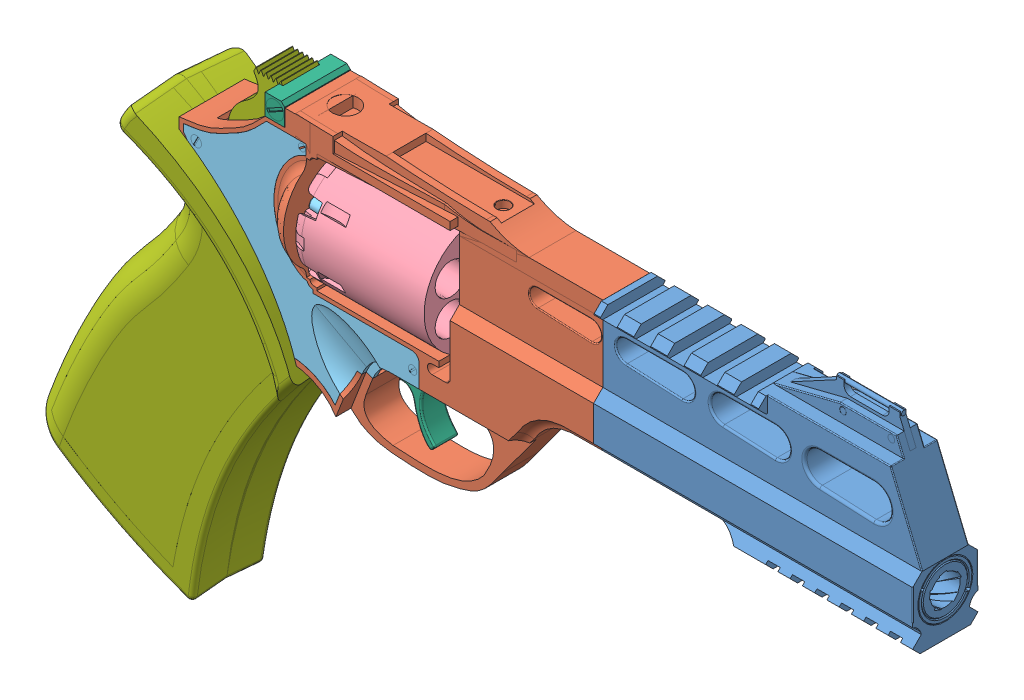
SolidWorks assembly Assem3, configuration Default. Lengths in mm.
Overall size (318.89 178.24 86.68).
34 component instances, 25 part files, 0 mates.
Components (placement in the parent):
- Part-1_1-1: Part-1_1 [Default] at (11.9965 32.6768 113.9743) size (116.03 64.57 23.76)
- Part-2b_1-1: Part-2b_1 [Default] at (-21.7434 30.6863 114.078) size (173.21 116.28 42.78)
- Comp_1-1: Comp_1 [Default] at (-13.7813 33.0136 111.9172) size (95.88 46.02 19.77)
- Cylinder and Nippel_1-1: Cylinder and Nippel_1 [Default] at (56.995 183.3088 108.2927) x (0.922784 -0.192659 0.333695) z (0 -0.866025 -0.5) size (60.74 56.25 42.91)
  - Cylinder 1858_1-1: Cylinder 1858_1 [Default] at (-281.0623 -165.5889 86.5959) size (60.74 56.25 42.91)
  - Nippel_1-1: Nippel_1 [Default] at (-226.4262 -248.8987 62.7661) x (0.958139 0.261772 0.115951) z (-0.137252 0.064549 0.988431) size (13.49 11.07 7.64)
  - Nippel_1-2: Nippel_1 [Default] at (-57.2361 288.5909 306.301) x (0.69579 -0.623349 -0.356808) z (0.47753 0.772559 -0.41847) size (13.49 11.07 7.64)
  - Nippel_1-3: Nippel_1 [Default] at (-281.0623 -165.5889 86.5959) size (13.49 11.07 7.64)
  - Nippel_1-4: Nippel_1 [Default] at (-257.1342 -199.4668 114.0435) x (0.988242 0.090682 -0.123105) z (0.130098 -0.075709 0.988606) size (13.49 11.07 7.64)
  - Nippel_1-5: Nippel_1 [Default] at (-215.3253 -254.1194 109.49) x (0.958139 0.261772 -0.115951) z (0.137252 -0.064549 0.988431) size (13.49 11.07 7.64)
  - Nippel_1-6: Nippel_1 [Default] at (-197.9583 -275.6951 86.5959) x (0.939693 0.34202 0) z (0 0 1) size (13.49 11.07 7.64)
- TRigger_1-1: TRigger_1 [Default] at (-1308.0404 -1190.4474 118.8218) x (0.981914 0.189327 0) z (0 0 1) size (21.87 34.66 8.65)
- Hammer_1-1: Hammer_1 [Default] at (-35.5126 36.5966 114.1094) size (26.46 31.09 13.23)
- Roller-1_1-1: Roller-1_1 [Default] at (-3.9075 114.1625 112.9787) x (0.74655 -0.66533 0) z (0 0 1) size (8.89 8.89 7.11)
- Spring_1-1: Spring_1 [Default] at (-17.4358 57.0675 123.8361) x (0.998565 -0.053556 0) z (0 0 1) size (17.15 30.92 6.73)
- Roller-1_1-2: Roller-1_1 [Default] at (-10.8089 88.3962 113.0344) x (0.941065 0.338225 0) z (0 0 1) size (8.89 8.89 7.11)
- Sylinder Stop Level_1-1: Sylinder Stop Level_1 [Default] at (56.163 93.2048 121.6948) x (0.99736 -0.072616 0) z (0 0 1) size (15.92 19.29 0.76)
- Level-1_1-1: Level-1_1 [Default] at (0.1659 -0.0827 121.6948) size (14.49 13.67 2.03)
- Single Action Level_1-1: Single Action Level_1 [Default] at (0 0 122.4568) size (15.9 9.34 0.76)
- Level-2_1-1: Level-2_1 [Default] at (45.7184 96.0003 120.9328) x (0.995526 0.094487 0) z (0 0 1) size (10.88 7.58 0.76)
- Washer_1-1: Washer_1 [Default] at (0 0 123.2188) size (5.59 5.59 0.38)
- Interlink Level_1-1: Interlink Level_1 [Default] at (1.5397 0.4861 120.1708) size (15.08 14.68 0.76)
- Level-3_1-1: Level-3_1 [Default] at (0 0 120.1708) size (27.72 20.89 0.76)
- Washer_1-2: Washer_1 [Default] at (-55.7165 15.1252 120.9328) x (0.911643 -0.410984 0) z (0 0 1) size (5.59 5.59 0.38)
- Return Level-1_1-1: Return Level-1_1 [Default] at (0.2327 -0.0811 120.1464) size (29.87 18 1.27)
- Cocking Lever_1-1: Cocking Lever_1 [Default] at (-21.9432 31.6954 126.9544) x (0.999997 -0.002422 0) z (0 0 1) size (14.7 40.87 2.54)
- Level-4_1-1: Level-4_1 [Default] at (10.0529 99.6563 120.3544) size (32.41 45.63 0.76)
- Return level-a_1-1: Return level-a_1 [Default] at (0 0 119.8924) size (24.34 19.46 0.76)
- Level-5_1-1: Level-5_1 [Default] at (-11.0551 3.7924 121.6604) x (0.990855 -0.134931 0) z (0 0 1) size (30.27 13.58 0.76)
- Washer_1-3: Washer_1 [Default] at (-21.9488 -10.3949 122.4284) x (0.999916 -0.012965 0) z (0 0 1) size (5.59 5.59 0.38)
- Level-6_1-1: Level-6_1 [Default] at (13.6029 82.0165 121.078) size (23.21 17.38 0.76)
- Cap-1_1-1: Cap-1_1 [Default] at (-21.7434 30.6863 132.0844) size (102.1 103.3 7.96)
- Tab_1-1: Tab_1 [Default] at (16.0588 150.9977 109.5944) size (7.11 7.62 23.88)
- Hand Grip_1-1: Hand Grip_1 [Default] at (0 0 -0.116) size (97.9 152.49 50.19)
